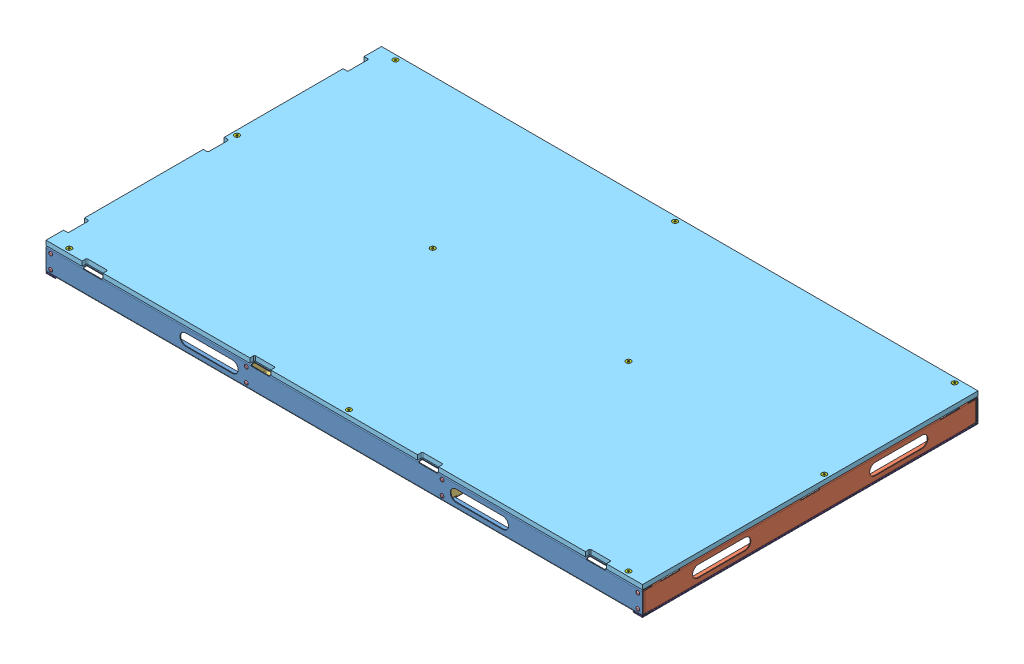
SolidWorks assembly GE-19067, configuration GE-19067-red. Lengths in mm.
Overall size (1625.6 77.99 917.59).
46 component instances, 8 part files, 49 mates.
Components (placement in the parent):
- GE-19063-1: GE-19063 [Default] at origin size (1625.6 63.5 917.59)
  - GE-19066-2: GE-19066 [Default] at (812.8 0 -457.2) x (0 0 -1) z (1 0 0) size (25.4 63.5 1625.6)
  - GE-19064-2: GE-19064 [Default] at (-812.8 0 -430.5376) x (-1 0 0) z (0 0 -1) size (25.4 63.5 910.59)
  - GE-19064-3: GE-19064 [Default] at (812.8 0 430.5224) size (25.4 63.5 910.59)
  - GE-19066-3: GE-19066 [Default] at (-812.8 0 457.1848) x (0 0 1) z (-1 0 0) size (25.4 63.5 1625.6)
  - GE-19065-1: GE-19065 [Default] at (279.4 0 -0.0076) size (25.4 63.5 910.59)
  - GE-19065-2: GE-19065 [Default] at (-279.4 63.5 -0.0076) x (-1 0 0) z (0 0 1) size (25.4 63.5 910.59)
  - rivet_.1875_.126-.25-2: rivet_.1875_.126-.25 [Default] at (-800.1 50.8 457.1848) size (10.01 10.01 13.03)
  - rivet_.1875_.126-.25-10: rivet_.1875_.126-.25 [Default] at (-266.7 50.8 457.1848) x (0.959125 0.282984 0) z (0 0 1) size (10.01 10.01 13.03)
  - rivet_.1875_.126-.25-11: rivet_.1875_.126-.25 [Default] at (-266.7 12.7 457.1848) x (0.928571 0.371154 0) z (0 0 1) size (10.01 10.01 13.03)
  - rivet_.1875_.126-.25-12: rivet_.1875_.126-.25 [Default] at (266.7 50.8 457.1848) x (0.906989 0.421154 0) z (0 0 1) size (10.01 10.01 13.03)
  - rivet_.1875_.126-.25-13: rivet_.1875_.126-.25 [Default] at (266.7 12.7 457.1848) x (0.902849 0.429957 0) z (0 0 1) size (10.01 10.01 13.03)
  - rivet_.1875_.126-.25-14: rivet_.1875_.126-.25 [Default] at (800.1 50.8 457.1848) x (0.919615 0.39282 0) z (0 0 1) size (10.01 10.01 13.03)
  - rivet_.1875_.126-.25-15: rivet_.1875_.126-.25 [Default] at (800.1 12.7 457.1848) x (0.952324 0.305088 0) z (0 0 1) size (10.01 10.01 13.03)
  - rivet_.1875_.126-.25-18: rivet_.1875_.126-.25 [Default] at (-800.1 12.7 457.1848) x (0.987351 0.158553 0) z (0 0 1) size (10.01 10.01 13.03)
  - rivet_.1875_.126-.25-20: rivet_.1875_.126-.25 [Default] at (800.1 50.8 -457.2) x (1 0 0) z (0 0 -1) size (10.01 10.01 13.03)
  - rivet_.1875_.126-.25-21: rivet_.1875_.126-.25 [Default] at (800.1 12.7 -457.2) x (0.987351 0.158553 0) z (0 0 -1) size (10.01 10.01 13.03)
  - rivet_.1875_.126-.25-22: rivet_.1875_.126-.25 [Default] at (266.7 50.8 -457.2) x (0.959125 0.282984 0) z (0 0 -1) size (10.01 10.01 13.03)
  - rivet_.1875_.126-.25-23: rivet_.1875_.126-.25 [Default] at (266.7 12.7 -457.2) x (0.928571 0.371154 0) z (0 0 -1) size (10.01 10.01 13.03)
  - rivet_.1875_.126-.25-24: rivet_.1875_.126-.25 [Default] at (-266.7 50.8 -457.2) x (0.906989 0.421154 0) z (0 0 -1) size (10.01 10.01 13.03)
  - rivet_.1875_.126-.25-25: rivet_.1875_.126-.25 [Default] at (-266.7 12.7 -457.2) x (0.902849 0.429957 0) z (0 0 -1) size (10.01 10.01 13.03)
  - rivet_.1875_.126-.25-26: rivet_.1875_.126-.25 [Default] at (-800.1 50.8 -457.2) x (0.919615 0.39282 0) z (0 0 -1) size (10.01 10.01 13.03)
  - rivet_.1875_.126-.25-27: rivet_.1875_.126-.25 [Default] at (-800.1 12.7 -457.2) x (0.952324 0.305088 0) z (0 0 -1) size (10.01 10.01 13.03)
- GE-19068-1: GE-19068 [GE-19068-red] at (812.8 76.2 457.1848) x (-1 0 0) z (0 0 1) size (1625.6 12.7 914.4)
- nylock_.25_20-1: nylock_.25_20 [Default] at (-762 61.6026 444.4848) x (-1 0 0) z (0 0 1) size (11.11 7.94 12.83)
- nylock_.25_20-2: nylock_.25_20 [Default] at (0 61.6026 444.4848) x (-0.982082 0 0.188455) z (0.188455 0 0.982082) size (11.11 7.94 12.83)
- nylock_.25_20-3: nylock_.25_20 [Default] at (762 61.6026 444.4848) x (-0.918365 0 0.395734) z (0.395734 0 0.918365) size (11.11 7.94 12.83)
- nylock_.25_20-4: nylock_.25_20 [Default] at (800.1 61.6026 -50.8076) x (-0.8 0 0.6) z (0.6 0 0.8) size (11.11 7.94 12.83)
- nylock_.25_20-5: nylock_.25_20 [Default] at (266.7 61.6026 -50.8076) x (-0.63358 0 0.773678) z (0.773678 0 0.63358) size (11.11 7.94 12.83)
- nylock_.25_20-8: nylock_.25_20 [Default] at (-800.1 61.6026 -50.8076) x (0.999877 0 -0.015704) z (-0.015704 0 -0.999877) size (11.11 7.94 12.83)
- nylock_.25_20-9: nylock_.25_20 [Default] at (-762 61.6026 -444.5) x (-0.263225 0 0.964735) z (0.964735 0 0.263225) size (11.11 7.94 12.83)
- nylock_.25_20-10: nylock_.25_20 [Default] at (0 61.6026 -444.5) x (-0.120178 0 0.992752) z (0.992752 0 0.120178) size (11.11 7.94 12.83)
- nylock_.25_20-11: nylock_.25_20 [Default] at (762 61.6026 -444.5) x (-0.030377 0 0.999538) z (0.999538 0 0.030377) size (11.11 7.94 12.83)
- nylock_.25_20-12: nylock_.25_20 [Default] at (-266.7 61.6026 -50.8076) x (0.546944 0 0.837169) z (0.837169 0 -0.546944) size (11.11 7.94 12.83)
- flat_hex_.25_20_1-1: flat_hex_.25_20_1 [91253A542] at (762 76.2 -444.5152) x (1 0 0) z (0 1 0) size (13.49 13.49 25.61)
- flat_hex_.25_20_1-12: flat_hex_.25_20_1 [91253A542] at (0 76.2 -444.5152) x (0.982082 0 -0.188455) z (0 1 0) size (13.49 13.49 25.61)
- flat_hex_.25_20_1-13: flat_hex_.25_20_1 [91253A542] at (-762 76.2 -444.5152) x (0.918365 0 -0.395734) z (0 1 0) size (13.49 13.49 25.61)
- flat_hex_.25_20_1-14: flat_hex_.25_20_1 [91253A542] at (-800.1 76.2 -50.8152) x (0.8 0 -0.6) z (0 1 0) size (13.49 13.49 25.61)
- flat_hex_.25_20_1-15: flat_hex_.25_20_1 [91253A542] at (-762 76.2 444.4848) x (0.63358 0 -0.773678) z (0 1 0) size (13.49 13.49 25.61)
- flat_hex_.25_20_1-16: flat_hex_.25_20_1 [91253A542] at (0 76.2 444.4848) x (0.443629 0 -0.896211) z (0 1 0) size (13.49 13.49 25.61)
- flat_hex_.25_20_1-17: flat_hex_.25_20_1 [91253A542] at (-266.7 76.2 -50.8152) x (0.263225 0 -0.964735) z (0 1 0) size (13.49 13.49 25.61)
- flat_hex_.25_20_1-18: flat_hex_.25_20_1 [91253A542] at (266.7 76.2 -50.8152) x (0.120178 0 -0.992752) z (0 1 0) size (13.49 13.49 25.61)
- flat_hex_.25_20_1-19: flat_hex_.25_20_1 [91253A542] at (762 76.2 444.4848) x (0.030377 0 -0.999538) z (0 1 0) size (13.49 13.49 25.61)
- flat_hex_.25_20_1-20: flat_hex_.25_20_1 [91253A542] at (800.1 76.2 -50.8152) x (0 0 -1) z (0 1 0) size (13.49 13.49 25.61)
- Hook_1_36-1: Hook_1_36 [Default] at (-787.4 -1.5875 457.2) x (0 0 -1) z (1 0 0) size (914.4 1.59 25.4)
- Hook_1_36-2: Hook_1_36 [Default] at (812.8 -1.5875 457.2) x (0 0 -1) z (1 0 0) size (914.4 1.59 25.4)
Mates (geometry in assembly coordinates):
- Concentric3: concentric: cylinder of GE-19063-1/GE-19066-3 through (-762 61.6026 444.4848) axis (0 1 0) radius 3.3655; cylinder of nylock_.25_20-1 through (-762 61.6026 444.4848) axis (0 -1 0) radius 3.175
- Coincident2: coincident: plane of GE-19063-1/GE-19066-3 through (-812.8 61.6026 457.1848) normal (0 -1 0); plane of nylock_.25_20-1 through (-762 61.6026 444.4848) normal (0 1 0)
- Concentric4: concentric: cylinder of GE-19063-1/GE-19066-3 through (0 61.6026 444.4848) axis (0 1 0) radius 3.3655; cylinder of nylock_.25_20-2 through (0 61.6026 444.4848) axis (0 -1 0) radius 3.175
- Coincident4: coincident: plane of GE-19063-1/GE-19066-3 through (-812.8 61.6026 457.1848) normal (0 -1 0); plane of nylock_.25_20-2 through (0 61.6026 444.4848) normal (0 1 0)
- Coincident5: coincident: plane of GE-19063-1/GE-19066-3 through (-812.8 61.6026 457.1848) normal (0 -1 0); plane of nylock_.25_20-3 through (762 61.6026 444.4848) normal (0 1 0)
- Concentric5: concentric: cylinder of GE-19063-1/GE-19066-3 through (762 61.6026 444.4848) axis (0 1 0) radius 3.3655; cylinder of nylock_.25_20-3 through (762 61.6026 444.4848) axis (0 -1 0) radius 3.175
- Coincident6: coincident: plane of GE-19063-1/GE-19066-3 through (-812.8 61.6026 457.1848) normal (0 -1 0); plane of nylock_.25_20-4 through (800.1 61.6026 -50.8076) normal (0 1 0)
- Concentric6: concentric: cylinder of GE-19063-1/GE-19064-3 through (800.1 61.6026 -50.8076) axis (0 1 0) radius 3.3655; cylinder of nylock_.25_20-4 through (800.1 61.6026 -50.8076) axis (0 -1 0) radius 3.175
- Coincident7: coincident: plane of GE-19063-1/GE-19066-3 through (-812.8 61.6026 457.1848) normal (0 -1 0); plane of nylock_.25_20-5 through (266.7 61.6026 -50.8076) normal (0 1 0)
- Concentric7: concentric: cylinder of GE-19063-1/GE-19065-1 through (266.7 0 -50.8076) axis (0 1 0) radius 3.3655; cylinder of nylock_.25_20-5 through (266.7 61.6026 -50.8076) axis (0 -1 0) radius 3.175
- Concentric9: concentric: cylinder of GE-19063-1/GE-19064-2 through (-800.1 61.6026 -50.8076) axis (0 1 0) radius 3.3655; cylinder of nylock_.25_20-8 through (-800.1 61.6026 -50.8076) axis (0 -1 0) radius 3.175
- Coincident11: coincident: plane of GE-19063-1/GE-19066-3 through (-812.8 61.6026 457.1848) normal (0 -1 0); plane of nylock_.25_20-8 through (-800.1 61.6026 -50.8076) normal (0 1 0)
- Coincident12: coincident: plane of GE-19063-1/GE-19066-3 through (-812.8 61.6026 457.1848) normal (0 -1 0); plane of nylock_.25_20-9 through (-762 61.6026 -444.5) normal (0 1 0)
- Concentric10: concentric: cylinder of GE-19063-1/GE-19066-2 through (-762 61.6026 -444.5) axis (0 1 0) radius 3.3655; cylinder of nylock_.25_20-9 through (-762 61.6026 -444.5) axis (0 -1 0) radius 3.175
- Coincident13: coincident: plane of GE-19063-1/GE-19066-3 through (-812.8 61.6026 457.1848) normal (0 -1 0); plane of nylock_.25_20-10 through (0 61.6026 -444.5) normal (0 1 0)
- Concentric11: concentric: cylinder of GE-19063-1/GE-19066-2 through (0 61.6026 -444.5) axis (0 1 0) radius 3.3655; cylinder of nylock_.25_20-10 through (0 61.6026 -444.5) axis (0 -1 0) radius 3.175
- Coincident14: coincident: plane of GE-19063-1/GE-19066-3 through (-812.8 61.6026 457.1848) normal (0 -1 0); plane of nylock_.25_20-11 through (762 61.6026 -444.5) normal (0 1 0)
- Concentric12: concentric: cylinder of GE-19063-1/GE-19066-2 through (762 61.6026 -444.5) axis (0 1 0) radius 3.3655; cylinder of nylock_.25_20-11 through (762 61.6026 -444.5) axis (0 -1 0) radius 3.175
- Coincident15: coincident: plane of GE-19063-1/GE-19066-3 through (-812.8 61.6026 457.1848) normal (0 -1 0); plane of nylock_.25_20-12 through (-266.7 61.6026 -50.8076) normal (0 1 0)
- Concentric13: concentric: cylinder of GE-19063-1/GE-19065-2 through (-266.7 63.5 -50.8076) axis (0 -1 0) radius 3.3655; cylinder of nylock_.25_20-12 through (-266.7 61.6026 -50.8076) axis (0 -1 0) radius 3.175
- Coincident16: coincident: plane of GE-19063-1/GE-19064-2 through (-812.8 63.5 -430.5376) normal (0 1 0); plane of GE-19068-1 through (812.8 63.5 457.1848) normal (0 -1 0)
- Concentric14: concentric: cylinder of GE-19063-1/GE-19066-3 through (-762 61.6026 444.4848) axis (0 1 0) radius 3.3655; cylinder of GE-19068-1 through (-762 76.2 444.4848) axis (0 1 0) radius 3.5712
- Parallel2: parallel: plane of GE-19063-1/GE-19064-2 through (-812.8 0 -430.5376) normal (-1 0 0); plane of GE-19068-1 through (-812.8 63.5 457.1848) normal (-1 0 0)
- Concentric16: concentric: cylinder of assembly; cylinder of assembly; cylinder of GE-19068-1 through (762 76.2 -444.5152) axis (0 1 0) radius 3.5712; cylinder of flat_hex_.25_20_1-1 through (762 50.8 -444.5152) axis (0 -1 0) radius 3.175
- Coincident18: coincident: plane of assembly; plane of assembly; plane of GE-19068-1 through (812.8 76.2 457.1848) normal (0 1 0); plane of flat_hex_.25_20_1-1 through (762 76.2 -441.3402) normal (0 1 0)
- Concentric17: concentric: cylinder of assembly; cylinder of assembly; cylinder of GE-19068-1 through (0 76.2 -444.5152) axis (0 1 0) radius 3.5712; cylinder of flat_hex_.25_20_1-12 through (0 50.8 -444.5152) axis (0 -1 0) radius 3.175
- Coincident19: coincident: plane of assembly; plane of assembly; plane of GE-19068-1 through (812.8 76.2 457.1848) normal (0 1 0); plane of flat_hex_.25_20_1-12 through (0.5983 76.2 -441.3971) normal (0 1 0)
- Coincident20: coincident: plane of assembly; plane of assembly; plane of GE-19068-1 through (812.8 76.2 457.1848) normal (0 1 0); plane of flat_hex_.25_20_1-13 through (-760.7435 76.2 -441.5994) normal (0 1 0)
- Concentric18: concentric: cylinder of assembly; cylinder of assembly; cylinder of GE-19068-1 through (-762 76.2 -444.5152) axis (0 1 0) radius 3.5712; cylinder of flat_hex_.25_20_1-13 through (-762 50.8 -444.5152) axis (0 -1 0) radius 3.175
- Coincident21: coincident: plane of assembly; plane of assembly; plane of GE-19068-1 through (812.8 76.2 457.1848) normal (0 1 0); plane of flat_hex_.25_20_1-14 through (-798.195 76.2 -48.2752) normal (0 1 0)
- Concentric19: concentric: cylinder of assembly; cylinder of assembly; cylinder of GE-19068-1 through (-800.1 76.2 -50.8152) axis (0 1 0) radius 3.5712; cylinder of flat_hex_.25_20_1-14 through (-800.1 50.8 -50.8152) axis (0 -1 0) radius 3.175
- Coincident22: coincident: plane of assembly; plane of assembly; plane of GE-19068-1 through (812.8 76.2 457.1848) normal (0 1 0); plane of flat_hex_.25_20_1-15 through (-759.5436 76.2 446.4964) normal (0 1 0)
- Concentric20: concentric: cylinder of assembly; cylinder of assembly; cylinder of GE-19068-1 through (-762 76.2 444.4848) axis (0 1 0) radius 3.5712; cylinder of flat_hex_.25_20_1-15 through (-762 50.8 444.4848) axis (0 -1 0) radius 3.175
- Coincident23: coincident: plane of assembly; plane of assembly; plane of GE-19068-1 through (812.8 76.2 457.1848) normal (0 1 0); plane of flat_hex_.25_20_1-16 through (2.8455 76.2 445.8933) normal (0 1 0)
- Concentric21: concentric: cylinder of assembly; cylinder of assembly; cylinder of GE-19068-1 through (0 76.2 444.4848) axis (0 1 0) radius 3.5712; cylinder of flat_hex_.25_20_1-16 through (0 50.8 444.4848) axis (0 -1 0) radius 3.175
- Coincident24: coincident: plane of assembly; plane of assembly; plane of GE-19068-1 through (812.8 76.2 457.1848) normal (0 1 0); plane of flat_hex_.25_20_1-17 through (-263.637 76.2 -49.9795) normal (0 1 0)
- Concentric22: concentric: cylinder of assembly; cylinder of assembly; cylinder of GE-19068-1 through (-266.7 76.2 -50.8152) axis (0 1 0) radius 3.5712; cylinder of flat_hex_.25_20_1-17 through (-266.7 50.8 -50.8152) axis (0 -1 0) radius 3.175
- Coincident25: coincident: plane of assembly; plane of assembly; plane of GE-19068-1 through (812.8 76.2 457.1848) normal (0 1 0); plane of flat_hex_.25_20_1-18 through (269.852 76.2 -50.4337) normal (0 1 0)
- Concentric23: concentric: cylinder of assembly; cylinder of assembly; cylinder of GE-19068-1 through (266.7 76.2 -50.8152) axis (0 1 0) radius 3.5712; cylinder of flat_hex_.25_20_1-18 through (266.7 50.8 -50.8152) axis (0 -1 0) radius 3.175
- Coincident26: coincident: plane of assembly; plane of assembly; plane of GE-19068-1 through (812.8 76.2 457.1848) normal (0 1 0); plane of flat_hex_.25_20_1-19 through (765.1735 76.2 444.5812) normal (0 1 0)
- Concentric24: concentric: cylinder of assembly; cylinder of assembly; cylinder of GE-19068-1 through (762 76.2 444.4848) axis (0 1 0) radius 3.5712; cylinder of flat_hex_.25_20_1-19 through (762 50.8 444.4848) axis (0 -1 0) radius 3.175
- Coincident27: coincident: plane of assembly; plane of assembly; plane of GE-19068-1 through (812.8 76.2 457.1848) normal (0 1 0); plane of flat_hex_.25_20_1-20 through (803.275 76.2 -50.8152) normal (0 1 0)
- Concentric25: concentric: cylinder of assembly; cylinder of assembly; cylinder of GE-19068-1 through (800.1 76.2 -50.8152) axis (0 1 0) radius 3.5712; cylinder of flat_hex_.25_20_1-20 through (800.1 50.8 -50.8152) axis (0 -1 0) radius 3.175
- Coincident28: coincident: plane of GE-19063-1/GE-19064-2 through (-812.8 0 -430.5376) normal (0 -1 0); plane of Hook_1_36-1 through (-787.4 0 457.2) normal (0 1 0)
- Coincident29: coincident: plane of GE-19063-1/GE-19066-2 through (812.8 0 -457.2) normal (0 0 -1); plane of Hook_1_36-1 through (-787.4 0 -457.2) normal (0 0 -1)
- Coincident30: coincident: plane of GE-19063-1/GE-19064-2 through (-787.4 0 430.5224) normal (1 0 0); plane of Hook_1_36-1 through (-787.4 0 457.2) normal (1 0 0)
- Coincident31: coincident: plane of GE-19063-1/GE-19064-3 through (812.8 0 430.5224) normal (0 -1 0); plane of Hook_1_36-2 through (812.8 0 457.2) normal (0 1 0)
- Coincident32: coincident: plane of GE-19063-1/GE-19066-2 through (812.8 0 -457.2) normal (0 0 -1); plane of Hook_1_36-2 through (812.8 0 -457.2) normal (0 0 -1)
- Coincident33: coincident: plane of GE-19063-1/GE-19064-3 through (787.4 0 -430.5376) normal (-1 0 0); plane of Hook_1_36-2 through (787.4 0 457.2) normal (-1 0 0)
